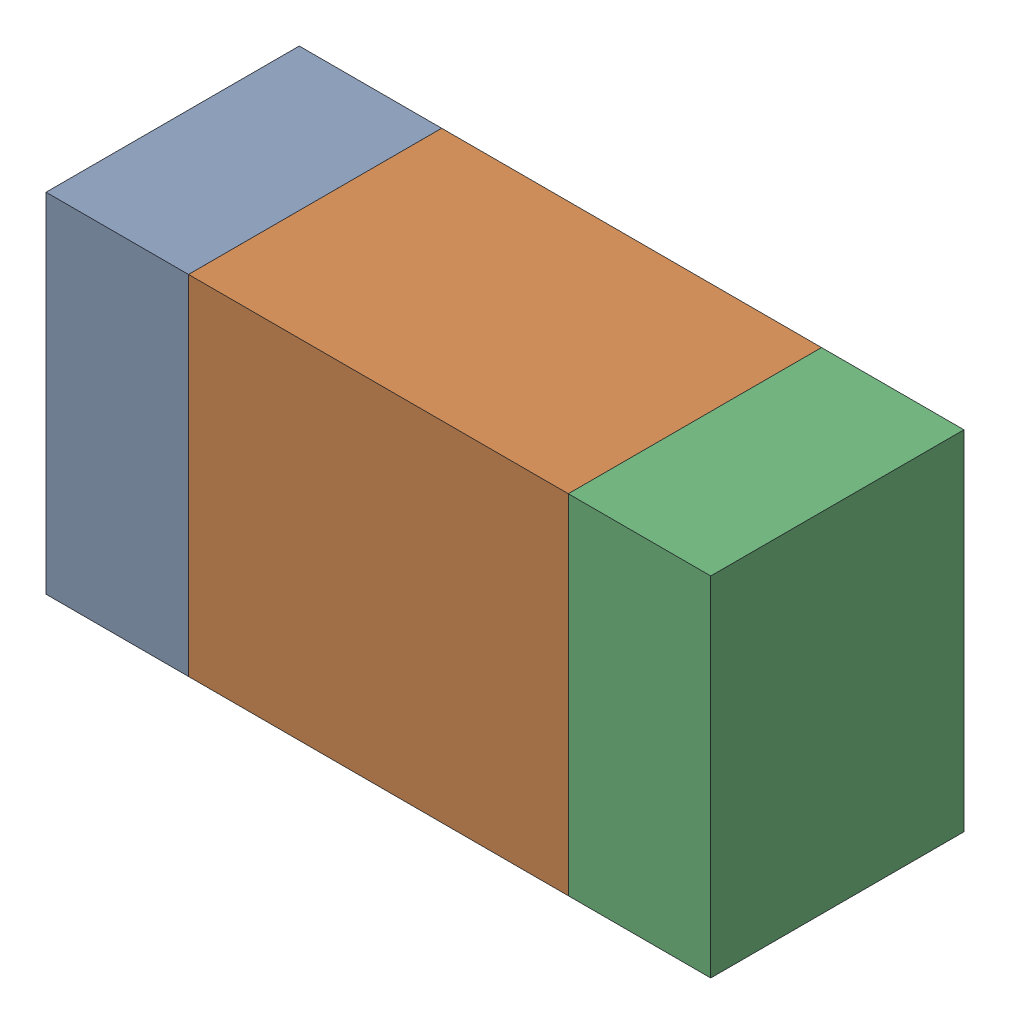
SolidWorks assembly R403PCB, configuration Default. Lengths in mm.
Overall size (1.05 0.55 0.4).
6 component instances, 2 part files, 0 mates.
Components (placement in the parent):
- 854785432-1: 854785432 [Default] at (88.1874 84.7999 0) size (0.22 0.55 0.4)
  - Extruded-1: Extruded [Default] at origin size (0.22 0.55 0.4)
- 854785568-1: 854785568 [Default] at (88.5999 84.7999 0) size (0.6 0.55 0.4)
  - Extruded_2-1: Extruded_2 [Default] at origin size (0.6 0.55 0.4)
- 854785432-2: 854785432 [Default] at (89.0124 84.7999 0) size (0.22 0.55 0.4)
  - Extruded-1: Extruded [Default] at origin size (0.22 0.55 0.4)
